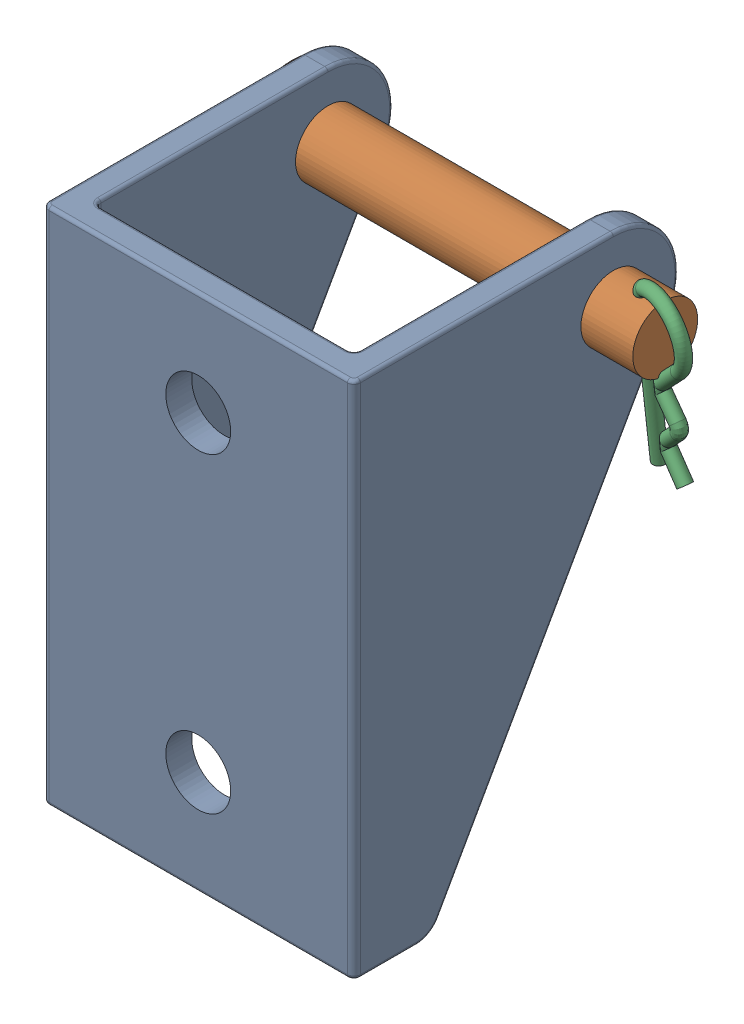
SolidWorks assembly 001_Assembly_LinearActuator, configuration Default. Lengths in mm.
Overall size (32.99 40 25).
3 component instances, 3 part files, 4 mates.
Components (placement in the parent):
- connection_009_LinearActuatorBracket-1: connection_009_LinearActuatorBracket [Default] at (-4.7523 -12.3057 7.7803) size (24 40 25)
- connection_010_LinearActuatorBolt-1: connection_010_LinearActuatorBolt [Default] at (11.2477 22.6943 -10.2197) x (0 -0.110841 0.993838) z (1 0 0) size (9 9 30)
- connection_011_LinearActuatorPin-1: connection_011_LinearActuatorPin [Default] at (9.7477 13.2528 -11.2726) x (0.972908 -0.025626 0.22977) z (0 -0.993838 -0.110841) size (5 1 13.6)
Mates (geometry in assembly coordinates):
- Coincident1: coincident anti-aligned: circle of connection_009_LinearActuatorBracket-1; cylinder of connection_010_LinearActuatorBolt-1 through (11.2477 22.6943 -10.2197) axis (1 0 0) radius 2.5
- Coincident2: coincident anti-aligned: plane of connection_009_LinearActuatorBracket-1 through (-16.7523 27.6943 9.2803) normal (-1 0 0); plane of connection_010_LinearActuatorBolt-1 through (-16.7523 23.193 -14.6919) normal (1 0 0)
- Concentric1: concentric anti-aligned: cylinder of connection_010_LinearActuatorBolt-1 through (9.7477 27.1665 -9.7209) axis (0 -0.993838 -0.110841) radius 0.5; cylinder of connection_011_LinearActuatorPin-1 through (9.7477 13.2528 -11.2726) axis (0 0.993838 0.110841) radius 0.5
- Tangent2: tangent: curve of connection_010_LinearActuatorBolt-1; circle of connection_011_LinearActuatorPin-1
